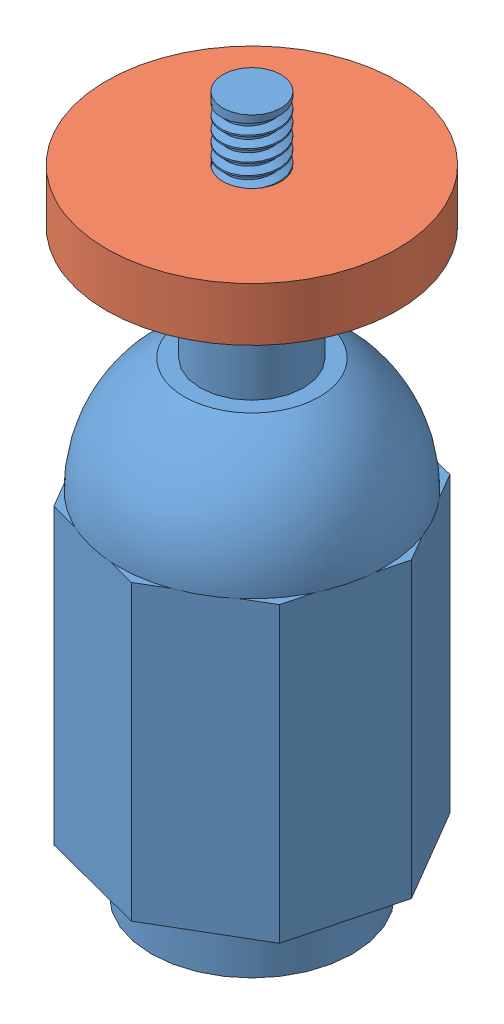
SolidWorks assembly pannaviseCameraMount, configuration Default. Lengths in mm.
Overall size (41.85 76 41.85).
2 component instances, 2 part files, 2 mates.
Components (placement in the parent):
- pannaviseCameraMount-1: pannaviseCameraMount [Default] at (19.7051 1.2918 63.159) size (30.55 76 30.55)
- pannaviseSpinnyThing-1: pannaviseSpinnyThing [Default] at (19.7051 64.5059 63.159) x (0.915223 0 0.402948) z (-0.402948 0 0.915223) size (31.75 7.17 31.75)
Mates (geometry in assembly coordinates):
- Screw1: screw = 1 aligned: line of pannaviseCameraMount-1 through (19.7051 77.2918 63.159) axis (0 -1 0); line of pannaviseSpinnyThing-1 through (19.7051 70.3479 63.159) axis (0 -1 0)
- LimitDistance1: limit distance = 0.0859 mm anti-aligned: plane of pannaviseSpinnyThing-1 through (19.7051 64.5059 63.159) normal (0 -1 0); plane of pannaviseCameraMount-1 through (19.7051 64.5918 63.159) normal (0 1 0)
